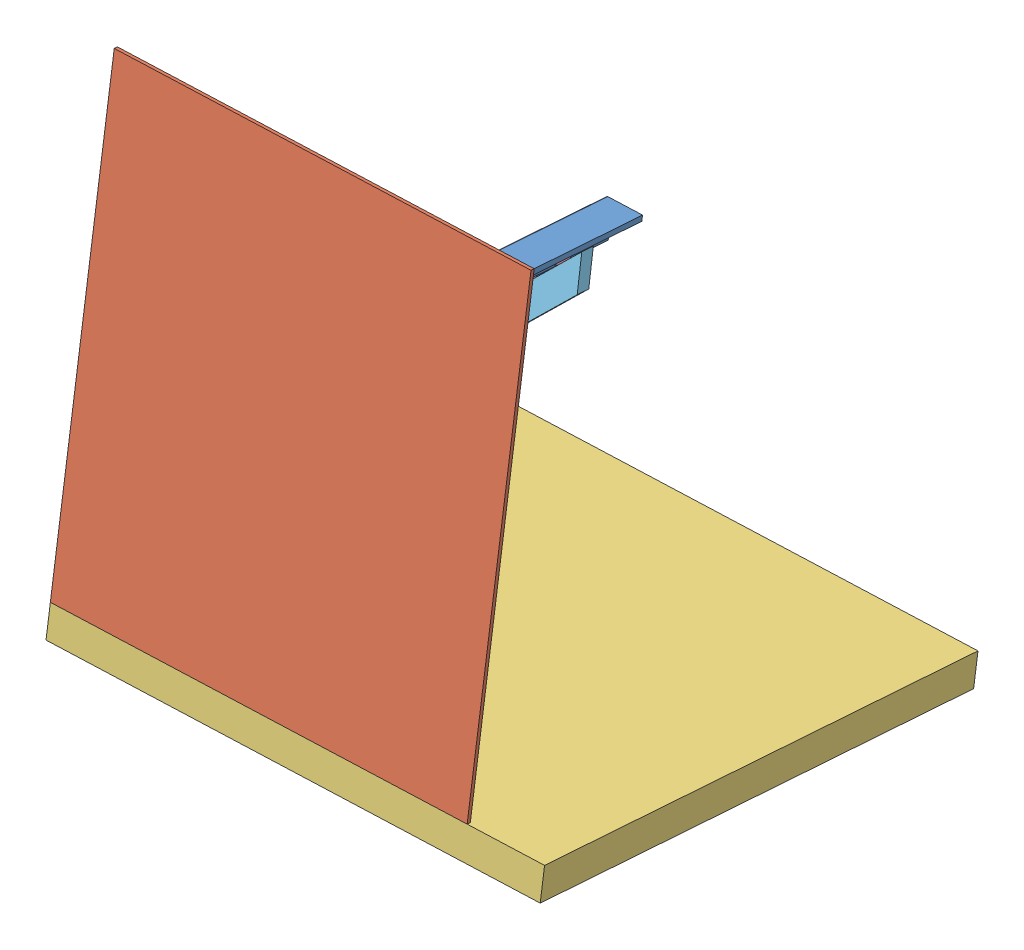
SolidWorks assembly limon debillarder, configuration Défaut. Lengths in mm.
Overall size (3181.92 3546.3 3175.24).
22 component instances, 8 part files, 73 mates.
Components (placement in the parent):
- marche 1 -2 exemplaire-7: marche 1 -2 exemplaire [Défaut] at (-2559.9044 2160.4734 676.1568) x (-0.998024 0.018673 0.059992) z (-0.061897 -0.12823 -0.989811) size (220 33 750)
- marche 1 -2 exemplaire-8: marche 1 -2 exemplaire [Défaut] at (-2378.2828 2338.8172 641.6947) x (-0.998024 0.018673 0.059992) z (-0.061897 -0.12823 -0.989811) size (220 33 750)
- marche 1 -2 exemplaire-9: marche 1 -2 exemplaire [Défaut] at (-2015.0395 2695.5048 572.7706) x (-0.998024 0.018673 0.059992) z (-0.061897 -0.12823 -0.989811) size (220 33 750)
- marche 1 -2 exemplaire-10: marche 1 -2 exemplaire [Défaut] at (-2196.6611 2517.161 607.2327) x (-0.998024 0.018673 0.059992) z (-0.061897 -0.12823 -0.989811) size (220 33 750)
- marche 1 -2 exemplaire-11: marche 1 -2 exemplaire [Défaut] at (-1651.7962 3052.1924 503.8465) x (-0.998024 0.018673 0.059992) z (-0.061897 -0.12823 -0.989811) size (220 33 750)
- marche 1 -2 exemplaire-12: marche 1 -2 exemplaire [Défaut] at (-1833.4179 2873.8486 538.3085) x (-0.998024 0.018673 0.059992) z (-0.061897 -0.12823 -0.989811) size (220 33 750)
- marche 1 -2 exemplaire-13: marche 1 -2 exemplaire [Défaut] at (-1470.1746 3230.5362 469.3844) x (-0.998024 0.018673 0.059992) z (-0.061897 -0.12823 -0.989811) size (220 33 750)
- marche 1 -2 exemplaire-14: marche 1 -2 exemplaire [Défaut] at (-1288.553 3408.88 434.9223) x (-0.998024 0.018673 0.059992) z (-0.061897 -0.12823 -0.989811) size (220 33 750)
- mur brique-1: mur brique [Défaut] at (-2859.8081 3139.9067 568.0256) x (0.998024 -0.018673 -0.059992) z (0.061897 0.12823 0.989811) size (2530 2932 22)
- DALLE2-2: DALLE2 [Défaut] at (-3845.6307 386.0727 1008.6592) x (-0.061897 -0.12823 -0.989811) z (0.998024 -0.018673 -0.059992) size (3000 200 3000)
- PLAFOND-1: PLAFOND [Défaut] at (-1253.4695 2570.9402 357.6002) x (1 0 0) z (0 1 0) size (3000 3000 200) (hidden)
- support de voile-3: support de voile [Défaut] at (-1513.939 3323.0655 -204.1342) x (0.998024 -0.018673 -0.059992) z (0.061897 0.12823 0.989811) size (190 139.32 565)
- support de voile-4: support de voile [Défaut] at (-1696.3813 3144.7371 -169.6228) x (0.998024 -0.018673 -0.059992) z (0.061897 0.12823 0.989811) size (190 139.32 565)
- support de voile-5: support de voile [Défaut] at (-2608.5927 2253.0948 2.9342) x (0.998024 -0.018673 -0.059992) z (0.061897 0.12823 0.989811) size (190 139.32 565)
- support de voile-7: support de voile [Défaut] at (-2243.7082 2609.7517 -66.0886) x (0.998024 -0.018673 -0.059992) z (0.061897 0.12823 0.989811) size (190 139.32 565)
- support de voile-8: support de voile [Défaut] at (-2426.1504 2431.4233 -31.5772) x (0.998024 -0.018673 -0.059992) z (0.061897 0.12823 0.989811) size (190 139.32 565)
- support de voile-9: support de voile [Défaut] at (-1878.8236 2966.4086 -135.1114) x (0.998024 -0.018673 -0.059992) z (0.061897 0.12823 0.989811) size (190 139.32 565)
- support de voile-10: support de voile [Défaut] at (-2791.1399 2074.7683 37.4519) x (0.998024 -0.018673 -0.059992) z (0.061897 0.12823 0.989811) size (190 139.32 565)
- support de voile-11: support de voile [Défaut] at (-2061.2659 2788.0802 -100.6) x (0.998024 -0.018673 -0.059992) z (0.061897 0.12823 0.989811) size (190 139.32 565)
- limon haut final-1: limon haut final [Défaut] at (-2050.1675 2656.0522 218.6036) x (-0.061897 -0.12823 -0.989811) z (0.998081 -0.009618 -0.061169) size (80 1697.72 1479.27)
- limon bas terminer-1: limon bas terminer [Défaut] at (-3449.8234 580.8535 -351.5753) x (0.061897 0.12823 0.989811) z (-0.998024 0.018673 0.059992) size (446.02 427.63 80)
- LIMON DEBILLARDER TERMINER-2: LIMON DEBILLARDER TERMINER [Défaut] at (-3502.6516 1564.6045 375.7017) size (690.88 1217.63 641.28)
Mates (geometry in assembly coordinates):
- Coïncidente294: coincident anti-aligned: plane of mur brique-1 through (-3843.4727 584.3864 982.8327) normal (-0.01079 -0.991569 0.129132); plane of DALLE2-2 through (-3843.4727 584.3864 982.8327) normal (0.01079 0.991569 -0.129132)
- Coïncidente295: coincident aligned: plane of mur brique-1 through (-3811.8364 3491.6657 604.2164) normal (-0.998024 0.018673 0.059992); plane of DALLE2-2 through (-3843.4727 584.3864 982.8327) normal (-0.998024 0.018673 0.059992)
- Coïncidente296: coincident aligned: plane of mur brique-1 through (-2858.4464 3142.7278 589.8014) normal (0.061897 0.12823 0.989811); plane of DALLE2-2 through (-3843.4727 584.3864 982.8327) normal (0.061897 0.12823 0.989811)
- Coïncidente297: coincident aligned: plane of marche 1 -2 exemplaire-14 through (-1554.1853 3349.5374 -298.4991) normal (0.01079 0.991569 -0.129132); plane of mur brique-1 through (-3811.8364 3491.6657 604.2164) normal (0.01079 0.991569 -0.129132)
- Coïncidente298: coincident aligned: plane of marche 1 -2 exemplaire-14 through (-1334.62 3345.4293 -311.6973) normal (0.998024 -0.018673 -0.059992); plane of mur brique-1 through (-1286.8352 3444.4229 452.4368) normal (0.998024 -0.018673 -0.059992)
- Coïncidente299: coincident anti-aligned: plane of marche 1 -2 exemplaire-13 through (-1470.1746 3230.5362 469.3844) normal (0.061897 0.12823 0.989811); plane of mur brique-1 through (-2859.8081 3139.9067 568.0256) normal (-0.061897 -0.12823 -0.989811)
- Coïncidente300: coincident anti-aligned: plane of marche 1 -2 exemplaire-11 through (-1651.7962 3052.1924 503.8465) normal (0.061897 0.12823 0.989811); plane of mur brique-1 through (-2859.8081 3139.9067 568.0256) normal (-0.061897 -0.12823 -0.989811)
- Coïncidente301: coincident anti-aligned: plane of marche 1 -2 exemplaire-12 through (-1833.4179 2873.8486 538.3085) normal (0.061897 0.12823 0.989811); plane of mur brique-1 through (-2859.8081 3139.9067 568.0256) normal (-0.061897 -0.12823 -0.989811)
- Coïncidente303: coincident anti-aligned: plane of marche 1 -2 exemplaire-9 through (-2015.0395 2695.5048 572.7706) normal (0.061897 0.12823 0.989811); plane of mur brique-1 through (-2859.8081 3139.9067 568.0256) normal (-0.061897 -0.12823 -0.989811)
- Coïncidente304: coincident anti-aligned: plane of marche 1 -2 exemplaire-14 through (-1288.553 3408.88 434.9223) normal (0.061897 0.12823 0.989811); plane of mur brique-1 through (-2859.8081 3139.9067 568.0256) normal (-0.061897 -0.12823 -0.989811)
- Coïncidente305: coincident anti-aligned: plane of marche 1 -2 exemplaire-10 through (-2196.6611 2517.161 607.2327) normal (0.061897 0.12823 0.989811); plane of mur brique-1 through (-2859.8081 3139.9067 568.0256) normal (-0.061897 -0.12823 -0.989811)
- Coïncidente306: coincident anti-aligned: plane of marche 1 -2 exemplaire-8 through (-2378.2828 2338.8172 641.6947) normal (0.061897 0.12823 0.989811); plane of mur brique-1 through (-2859.8081 3139.9067 568.0256) normal (-0.061897 -0.12823 -0.989811)
- Coïncidente307: coincident anti-aligned: plane of marche 1 -2 exemplaire-7 through (-2559.9044 2160.4734 676.1568) normal (0.061897 0.12823 0.989811); plane of mur brique-1 through (-2859.8081 3139.9067 568.0256) normal (-0.061897 -0.12823 -0.989811)
- Distance138: distance = 183.25 mm aligned: plane of marche 1 -2 exemplaire-14 through (-1554.1853 3349.5374 -298.4991) normal (0.01079 0.991569 -0.129132); plane of marche 1 -2 exemplaire-13 through (-1735.8069 3171.1936 -264.037) normal (0.01079 0.991569 -0.129132)
- Distance139: distance = 40 mm anti-aligned: plane of marche 1 -2 exemplaire-14 through (-1554.5414 3316.8156 -294.2377) normal (-0.998024 0.018673 0.059992); plane of marche 1 -2 exemplaire-13 through (-1516.2416 3167.0855 -277.2352) normal (0.998024 -0.018673 -0.059992)
- Distance140: distance = 183.25 mm aligned: plane of marche 1 -2 exemplaire-13 through (-1735.8069 3171.1936 -264.037) normal (0.01079 0.991569 -0.129132); plane of marche 1 -2 exemplaire-11 through (-1917.4286 2992.8498 -229.5749) normal (0.01079 0.991569 -0.129132)
- Distance141: distance = 40 mm anti-aligned: plane of marche 1 -2 exemplaire-11 through (-1697.8632 2988.7417 -242.7732) normal (0.998024 -0.018673 -0.059992); plane of marche 1 -2 exemplaire-13 through (-1736.163 3138.4718 -259.7756) normal (-0.998024 0.018673 0.059992)
- Distance142: distance = 183.25 mm aligned: plane of marche 1 -2 exemplaire-12 through (-2099.0502 2814.506 -195.1129) normal (0.01079 0.991569 -0.129132); plane of marche 1 -2 exemplaire-11 through (-1917.4286 2992.8498 -229.5749) normal (0.01079 0.991569 -0.129132)
- Distance143: distance = 40 mm anti-aligned: plane of marche 1 -2 exemplaire-12 through (-1879.4849 2810.3979 -208.3111) normal (0.998024 -0.018673 -0.059992); plane of marche 1 -2 exemplaire-11 through (-1917.7846 2960.128 -225.3136) normal (-0.998024 0.018673 0.059992)
- Distance144: distance = 183.25 mm aligned: plane of marche 1 -2 exemplaire-9 through (-2280.6718 2636.1622 -160.6508) normal (0.01079 0.991569 -0.129132); plane of marche 1 -2 exemplaire-12 through (-2099.0502 2814.506 -195.1129) normal (0.01079 0.991569 -0.129132)
- Distance145: distance = 40 mm anti-aligned: plane of marche 1 -2 exemplaire-12 through (-2099.4063 2781.7842 -190.8515) normal (-0.998024 0.018673 0.059992); plane of marche 1 -2 exemplaire-9 through (-2061.1065 2632.0541 -173.849) normal (0.998024 -0.018673 -0.059992)
- Distance147: distance = 183.25 mm aligned: plane of marche 1 -2 exemplaire-9 through (-2280.6718 2636.1622 -160.6508) normal (0.01079 0.991569 -0.129132); plane of marche 1 -2 exemplaire-10 through (-2462.2934 2457.8184 -126.1887) normal (0.01079 0.991569 -0.129132)
- Distance148: distance = 183.25 mm aligned: plane of marche 1 -2 exemplaire-8 through (-2643.9151 2279.4746 -91.7267) normal (0.01079 0.991569 -0.129132); plane of marche 1 -2 exemplaire-10 through (-2462.2934 2457.8184 -126.1887) normal (0.01079 0.991569 -0.129132)
- Distance149: distance = 183.25 mm aligned: plane of marche 1 -2 exemplaire-7 through (-2825.5367 2101.1308 -57.2646) normal (0.01079 0.991569 -0.129132); plane of marche 1 -2 exemplaire-8 through (-2643.9151 2279.4746 -91.7267) normal (0.01079 0.991569 -0.129132)
- Distance150: distance = 183.25 mm aligned: plane of marche balancé 6-1 through (-2552.3305 1827.8809 -425.5588) normal (0.023177 0.991583 -0.127382); plane of marche 1 -2 exemplaire-7 through (-2825.5367 2101.1308 -57.2646) normal (0.01079 0.991569 -0.129132)
- Distance152: distance = 40 mm anti-aligned: plane of marche 1 -2 exemplaire-9 through (-2281.0279 2603.4404 -156.3894) normal (-0.998024 0.018673 0.059992); plane of marche 1 -2 exemplaire-10 through (-2242.7281 2453.7103 -139.387) normal (0.998024 -0.018673 -0.059992)
- Distance153: distance = 40 mm anti-aligned: plane of marche 1 -2 exemplaire-10 through (-2462.6495 2425.0966 -121.9274) normal (-0.998024 0.018673 0.059992); plane of marche 1 -2 exemplaire-8 through (-2424.3497 2275.3665 -104.9249) normal (0.998024 -0.018673 -0.059992)
- Distance154: distance = 40 mm anti-aligned: plane of marche 1 -2 exemplaire-7 through (-2605.9714 2097.0227 -70.4628) normal (0.998024 -0.018673 -0.059992); plane of marche 1 -2 exemplaire-8 through (-2644.2711 2246.7528 -87.4653) normal (-0.998024 0.018673 0.059992)
- Coïncidente326: coincident aligned: plane of marche 1 -2 exemplaire-14 through (-1334.62 3345.4293 -311.6973) normal (0.998024 -0.018673 -0.059992); plane of support de voile-3 through (-1294.2785 3397.0188 343.3648) normal (0.998024 -0.018673 -0.059992)
- Coïncidente327: coincident anti-aligned: plane of marche 1 -2 exemplaire-14 through (-1334.9761 3312.7076 -307.4359) normal (-0.01079 -0.991569 0.129132); plane of support de voile-3 through (-1483.9031 3400.5667 354.7633) normal (0.01079 0.991569 -0.129132)
- Distance174: distance = 2.5 mm: plane of support de voile-3 through (-1309.4434 3365.6024 100.8611) normal (0.061897 0.12823 0.989811); line of limon haut final-1 through (-1309.721 3137.1202 133.0041) axis (0.001677 0.991698 -0.128579)
- Coïncidente330: coincident: line of support de voile-10 through (-2718.2143 1983.6924 367.9844) axis (-0.061897 -0.12823 -0.989811); plane of limon haut final-1 through (-2788.2411 1915.4139 383.7347) normal (-0.702821 0.709746 -0.047997)
- Coïncidente331: coincident anti-aligned: plane of marche 1 -2 exemplaire-7 through (-2606.3274 2064.3009 -66.2014) normal (-0.01079 -0.991569 0.129132); plane of support de voile-10 through (-2761.104 2152.2695 596.3494) normal (0.01079 0.991569 -0.129132)
- Coïncidente332: coincident aligned: line of support de voile-3 through (-1309.4973 3360.6446 101.5068) axis (-0.061897 -0.12823 -0.989811); line of limon haut final-1 through (-1309.3426 3360.9652 103.9813) axis (-0.061897 -0.12823 -0.989811)
- Coïncidente333: coincident: line of support de voile-5 through (-2404.1511 2290.6739 308.5752) axis (-0.061897 -0.12823 -0.989811); plane of limon haut final-1 through (-2788.2411 1915.4139 383.7347) normal (-0.702821 0.709746 -0.047997)
- Coïncidente334: coincident anti-aligned: plane of marche 1 -2 exemplaire-8 through (-2424.7058 2242.6447 -100.6635) normal (-0.01079 -0.991569 0.129132); plane of support de voile-5 through (-2578.5569 2330.5959 561.8317) normal (0.01079 0.991569 -0.129132)
- Coïncidente335: coincident: line of support de voile-8 through (-2221.7088 2469.0023 274.0638) axis (-0.061897 -0.12823 -0.989811); plane of limon haut final-1 through (-2788.2411 1915.4139 383.7347) normal (-0.702821 0.709746 -0.047997)
- Coïncidente336: coincident anti-aligned: plane of marche 1 -2 exemplaire-10 through (-2243.0842 2420.9885 -135.1256) normal (-0.01079 -0.991569 0.129132); plane of support de voile-8 through (-2396.1146 2508.9244 527.3203) normal (0.01079 0.991569 -0.129132)
- Coïncidente337: coincident: line of support de voile-11 through (-1856.8242 2825.6592 205.041) axis (-0.061897 -0.12823 -0.989811); plane of limon haut final-1 through (-2788.2411 1915.4139 383.7347) normal (-0.702821 0.709746 -0.047997)
- Coïncidente338: coincident anti-aligned: plane of marche 1 -2 exemplaire-12 through (-1879.8409 2777.6761 -204.0497) normal (-0.01079 -0.991569 0.129132); plane of support de voile-11 through (-2031.23 2865.5813 458.2975) normal (0.01079 0.991569 -0.129132)
- Coïncidente339: coincident: line of support de voile-7 through (-2039.2665 2647.3308 239.5524) axis (-0.061897 -0.12823 -0.989811); plane of limon haut final-1 through (-2788.2411 1915.4139 383.7347) normal (-0.702821 0.709746 -0.047997)
- Coïncidente340: coincident anti-aligned: plane of marche 1 -2 exemplaire-9 through (-2061.4626 2599.3323 -169.5876) normal (-0.01079 -0.991569 0.129132); plane of support de voile-7 through (-2213.6723 2687.2528 492.8089) normal (0.01079 0.991569 -0.129132)
- Coïncidente341: coincident: line of support de voile-9 through (-1674.3819 3003.9877 170.5296) axis (-0.061897 -0.12823 -0.989811); plane of limon haut final-1 through (-2788.2411 1915.4139 383.7347) normal (-0.702821 0.709746 -0.047997)
- Coïncidente342: coincident anti-aligned: plane of marche 1 -2 exemplaire-11 through (-1698.2193 2956.0199 -238.5118) normal (-0.01079 -0.991569 0.129132); plane of support de voile-9 through (-1848.7877 3043.9097 423.7861) normal (0.01079 0.991569 -0.129132)
- Coïncidente344: coincident anti-aligned: line of support de voile-4 through (-1491.9396 3182.3161 136.0182) axis (-0.061897 -0.12823 -0.989811); plane of limon haut final-1 through (-2788.2411 1915.4139 383.7347) normal (-0.702821 0.709746 -0.047997)
- Coïncidente345: coincident anti-aligned: plane of marche 1 -2 exemplaire-13 through (-1516.5977 3134.3638 -272.9739) normal (-0.01079 -0.991569 0.129132); plane of support de voile-4 through (-1666.3454 3222.2382 389.2747) normal (0.01079 0.991569 -0.129132)
- Coïncidente346: coincident aligned: plane of support de voile-3 through (-1314.0857 3355.9852 26.6253) normal (-0.061897 -0.12823 -0.989811); plane of support de voile-4 through (-1496.528 3177.6567 61.1367) normal (-0.061897 -0.12823 -0.989811)
- Coïncidente347: coincident aligned: plane of support de voile-4 through (-1496.528 3177.6567 61.1367) normal (-0.061897 -0.12823 -0.989811); plane of support de voile-9 through (-1678.9703 2999.3283 95.6481) normal (-0.061897 -0.12823 -0.989811)
- Coïncidente349: coincident aligned: plane of support de voile-9 through (-1883.7597 2971.4598 -135.4571) normal (-0.061897 -0.12823 -0.989811); plane of support de voile-11 through (-2066.202 2793.1314 -100.9457) normal (-0.061897 -0.12823 -0.989811)
- Coïncidente350: coincident aligned: plane of support de voile-7 through (-2248.6443 2614.8029 -66.4343) normal (-0.061897 -0.12823 -0.989811); plane of support de voile-8 through (-2431.0866 2436.4745 -31.9229) normal (-0.061897 -0.12823 -0.989811)
- Coïncidente351: coincident aligned: plane of support de voile-7 through (-2248.6443 2614.8029 -66.4343) normal (-0.061897 -0.12823 -0.989811); plane of support de voile-11 through (-2066.202 2793.1314 -100.9457) normal (-0.061897 -0.12823 -0.989811)
- Coïncidente352: coincident aligned: plane of support de voile-5 through (-2613.5289 2258.146 2.5885) normal (-0.061897 -0.12823 -0.989811); plane of support de voile-8 through (-2431.0866 2436.4745 -31.9229) normal (-0.061897 -0.12823 -0.989811)
- Coïncidente353: coincident aligned: plane of support de voile-5 through (-2613.5289 2258.146 2.5885) normal (-0.061897 -0.12823 -0.989811); plane of support de voile-10 through (-2796.0761 2079.8195 37.1062) normal (-0.061897 -0.12823 -0.989811)
- Distance175: distance = 92.5 mm anti-aligned: plane of support de voile-3 through (-1483.9031 3400.5667 354.7633) normal (0.061897 0.12823 0.989811); plane of mur brique-1 through (-2859.8081 3139.9067 568.0256) normal (-0.061897 -0.12823 -0.989811)
- Coïncidente355: coincident aligned: plane of support de voile-10 through (-2796.0761 2079.8195 37.1062) normal (-0.061897 -0.12823 -0.989811); plane of support premiere marche balancé-1 through (-1272.2497 1936.2819 789.4078) normal (-0.061897 -0.12823 -0.989811)
- Coïncidente357: coincident: line of marche 1 -2 exemplaire-8 through (-2424.7058 2242.6447 -100.6635) axis (0.061897 0.12823 0.989811); plane of limon haut final-1 through (-2788.2411 1915.4139 383.7347) normal (-0.702821 0.709746 -0.047997)
- Coïncidente365: coincident anti-aligned: plane of support de voile-2 through (-102.0065 577.7184 463.1016) normal (-0.00135 0.999943 -0.010559); plane of marche 1 -2 exemplaire-15 through (-497.4508 740.1423 397.5238) normal (-0.078094 -0.99511 0.060474)
- Coïncidente374: coincident anti-aligned: plane of marche balancé 3-1 through (-1125.6973 1253.6146 -157.6207) normal (-0.069005 -0.991739 0.108129); plane of support 4 eme marche balancé-1 through (-961.6978 1363.1431 951.6109) normal (0.069005 0.991739 -0.108129)
- Coïncidente392: coincident anti-aligned: plane of limon haut final-1 through (-1052.0425 1166.3464 1349.3893) normal (0 -0.711806 -0.702376); plane of Pièce4-1 through (-430.4344 958.8428 1571.84) normal (0 0.711806 0.702376)
- Tangent17: tangent aligned: plane of limon haut final-1 through (-2793.1929 1905.1555 304.5498) normal (-0.061897 -0.12823 -0.989811); face of ?
- Coïncidente393: coincident: point of assembly; face of ?; point of assembly; face of ?; point of limon haut final-1; point of Pièce4-1
- Tangent19: tangent aligned: plane of limon haut final-1 through (-2788.2411 1915.4139 383.7347) normal (-0.702821 0.709746 -0.047997); edge_curve of ?
- Distance180: distance = 183.5 mm aligned: plane of marche balancé 5-2 through (-376.0542 1640.7538 86.3692) normal (0.096162 0.991948 -0.082419); plane of marche balancé 6-1 through (-2552.3305 1827.8809 -425.5588) normal (0.023177 0.991583 -0.127382)
- Distance181: distance = 183.25 mm aligned: plane of marche balance 4-1 through (-336.0898 1411.5885 -227.099) normal (0.078925 0.991801 -0.100508); plane of marche balancé 5-2 through (-376.0542 1640.7538 86.3692) normal (0.096162 0.991948 -0.082419)
- Distance186: distance = 183.25 mm aligned: plane of marche 1 -2 exemplaire-15 through (-476.2921 758.2309 176.8111) normal (0.078094 0.99511 -0.060474); plane of marche balancé 1-1 through (-551.7088 980.7909 615.7856) normal (0.084469 0.994644 -0.059569)
- Distance187: distance = 183.25 mm aligned: plane of marche balance 4-1 through (-336.0898 1411.5885 -227.099) normal (0.078925 0.991801 -0.100508); plane of marche balancé 3-1 through (-1123.4201 1286.342 -161.189) normal (0.069005 0.991739 -0.108129)
- Distance189: distance = 183.25 mm aligned: plane of 2 EME MARCHE BALANCER-2 through (-469.3596 1149.0077 641.5166) normal (0.057598 0.992086 -0.111567); plane of marche balancé 3-1 through (-1123.4201 1286.342 -161.189) normal (0.069005 0.991739 -0.108129)
- Distance190: distance = 10 mm anti-aligned: plane of DALLE2-2 through (-3843.4727 584.3864 982.8327) normal (0.01079 0.991569 -0.129132); plane of limon bas terminer-1 through (-3453.1365 415.9499 -355.3644) normal (-0.01079 -0.991569 0.129132)
- Distance191: distance = 2155 mm: line of limon bas terminer-1 through (-3502.1574 895.7612 13.2913) axis (-0.051217 -0.794849 -0.604642); line of limon haut final-1 through (-1314.2944 3350.7068 24.7964) axis (-0.001677 -0.991698 0.128579)
- Distance192: distance = 1300 mm: plane of mur brique-1 through (-2859.8081 3139.9067 568.0256) normal (-0.061897 -0.12823 -0.989811); line of limon bas terminer-1 through (-3453.1365 415.9499 -355.3644) axis (-0.998024 0.018673 0.059992)
- Coïncidente394: coincident anti-aligned: plane of limon haut final-1 through (-2790.8507 1203.387 453.1147) normal (-0.998081 0.009618 0.061169); plane of LIMON DEBILLARDER TERMINER-2 through (-2794.8384 1557.7835 332.3225) normal (0.998081 -0.009618 -0.061169)
- Coïncidente395: coincident anti-aligned: line of limon haut final-1 through (-2793.1929 1905.1555 304.5498) axis (-0.001677 -0.991698 0.128579); line of LIMON DEBILLARDER TERMINER-2 through (-2793.5714 1681.3106 333.5726) axis (0.001677 0.991698 -0.128579)
- Coïncidente396: coincident aligned: line of limon haut final-1 through (-2788.6196 1691.569 412.7575) axis (-0.061897 -0.12823 -0.989811); line of LIMON DEBILLARDER TERMINER-2 through (-2788.6196 1691.569 412.7575) axis (-0.061897 -0.12823 -0.989811)
